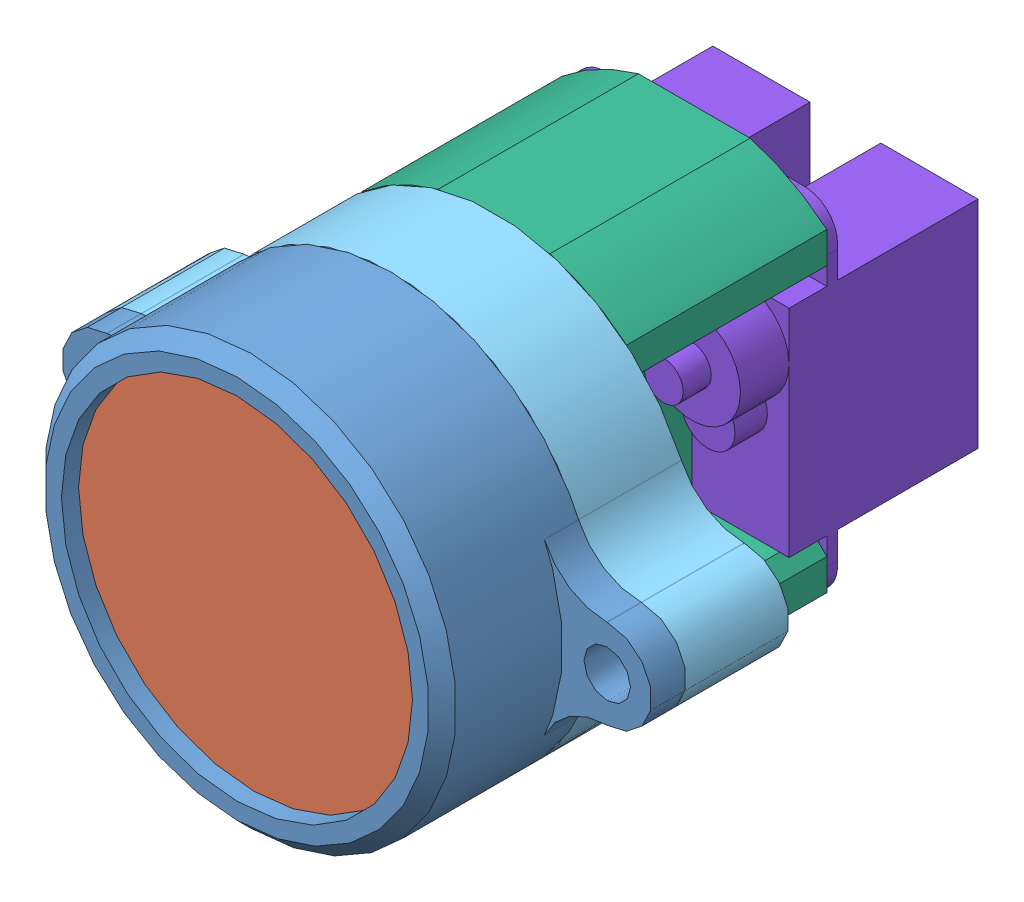
SolidWorks assembly Battery Voltage Indicator, configuration Default. Lengths in mm.
Overall size (132.95 120.76 56.35).
32 component instances, 13 part files, 60 mates.
Components (placement in the parent):
- 1.5 IN Case-1: 1.5 IN Case [Default] x (1 0 0) z (0 -1 0) size (54.61 14.29 38.1)
- 1.5 Indicator Glass-1: 1.5 Indicator Glass [Default] at (0 0 -1.5875) x (-1 0 0) z (0 0 -1) size (32.84 32.84 1.59)
- Battery Voltage Indicator Spacer-1: Battery Voltage Indicator Spacer [Default] at (0 0 -3.175) x (-1 0 0) z (0 0 -1) size (32.84 32.84 6.35)
- Battery Voltage Indicator Bezel Face-1: Battery Voltage Indicator Bezel Face [Default] at (0 0 -11.1125) x (-1 0 0) z (0 0 1) size (32.84 32.84 1.59)
- 1.5 Indicator Rear Bezel Spacer-1: 1.5 Indicator Rear Bezel Spacer [Default] at (0 0 -11.1125) x (1 0 0) z (0 0 -1) size (54.61 38.1 12.7)
- Battery Voltage Servo Mount-1: Battery Voltage Servo Mount [Default] at (0 0 -23.8125) x (1 0 0) z (0 0 -1) size (24.55 36.67 18.54)
- Battery Voltage Pointer-1: Battery Voltage Pointer [#1 Needle] at (0 0 -9.525) x (0.438476 0.898743 0) z (0 0 1) size (8.26 15.24 1.59)
- spur gear_ai-2: spur gear_ai [PreviewCfg] at (0 0 -25.4) x (0 0 -1) z (0.923728 0.383049 0) size (12.7 86.43 86.43)
- spur gear_ai-3: spur gear_ai [PreviewCfg] at (-7.7766 5.5 -38.1) x (0 0 1) z (-0.47771 -0.878518 0) size (12.7 86.43 86.43)
- SERVO, SUB-NANO, 3.7G, GENERIC-2: SERVO, SUB-NANO, 3.7G, GENERIC [Default] at (-12.2766 -10 -56.35) size (9.5 32.5 24.6)
- Battery Voltage Pointer-2: Battery Voltage Pointer [#2 Needle] at (0 0 -7.1437) x (0.44703 -0.894519 0) z (0 0 1) size (8.26 15.24 1.59)
- spur gear_ai-4: spur gear_ai [PreviewCfg] at (0 0 -30.1625) x (0 0 -1) z (0.923728 0.383049 0) size (12.7 86.43 86.43)
- spur gear_ai-5: spur gear_ai [PreviewCfg] at (7.7766 5.5 -33.3375) x (0 0 1) z (-0.486959 -0.873425 0) size (12.7 86.43 86.43)
- SERVO, SUB-NANO, 3.7G, GENERIC-1: SERVO, SUB-NANO, 3.7G, GENERIC [Default] at (3.2766 -10 -56.35) size (9.5 32.5 24.6)
- 93365A130_BRASS HEAT-SET INSERT FOR PLASTICS_6-32-3: 93365A130_BRASS HEAT-SET INSERT FOR PLASTICS_6-32 [93365A130] at (-23.1775 0 -14.2875) x (1 0 0) z (0 -1 0) size (5.56 4.29 5.56)
- 93365A130_BRASS HEAT-SET INSERT FOR PLASTICS_6-32-4: 93365A130_BRASS HEAT-SET INSERT FOR PLASTICS_6-32 [93365A130] at (23.1775 0 -14.2875) x (0.987351 0.158553 0) z (0.158553 -0.987351 0) size (5.56 4.29 5.56)
- 93365A102 - INSERT, 0-80, BRASS, FOR PLASTICS-1: 93365A102 - INSERT, 0-80, BRASS, FOR PLASTICS [Default] at (-7.7766 -13 -42.35) x (-0.989224 0.146409 0) z (-0.146409 -0.989224 0) size (3.58 3.01 3.58)
- 91772A061_18-8 SS PAN HEAD PHILLIPS MACHINE SCREW_#0-80 X .2812-1: 91772A061_18-8 SS PAN HEAD PHILLIPS MACHINE SCREW_#0-80 X .2812 [91772A061] at (-7.7766 -13 -36.2063) x (-0.460399 -0.887712 0) z (0 0 -1) size (2.95 2.95 8.26)
- 93365A102 - INSERT, 0-80, BRASS, FOR PLASTICS-2: 93365A102 - INSERT, 0-80, BRASS, FOR PLASTICS [Default] at (-7.7766 13 -42.35) x (-0.989224 0.146409 0) z (-0.146409 -0.989224 0) size (3.58 3.01 3.58)
- 93365A102 - INSERT, 0-80, BRASS, FOR PLASTICS-3: 93365A102 - INSERT, 0-80, BRASS, FOR PLASTICS [Default] at (7.7766 13 -42.35) x (-0.989224 0.146409 0) z (-0.146409 -0.989224 0) size (3.58 3.01 3.58)
- 93365A102 - INSERT, 0-80, BRASS, FOR PLASTICS-4: 93365A102 - INSERT, 0-80, BRASS, FOR PLASTICS [Default] at (7.7766 -13 -42.35) x (-0.989224 0.146409 0) z (-0.146409 -0.989224 0) size (3.58 3.01 3.58)
- 93365A102 - INSERT, 0-80, BRASS, FOR PLASTICS-5: 93365A102 - INSERT, 0-80, BRASS, FOR PLASTICS [Default] at (7.435 -14.69 -23.8125) x (0.989224 0.146409 0) z (0.146409 -0.989224 0) size (3.58 3.01 3.58)
- 93365A102 - INSERT, 0-80, BRASS, FOR PLASTICS-6: 93365A102 - INSERT, 0-80, BRASS, FOR PLASTICS [Default] at (-7.7474 -14.6946 -23.8125) x (0.989224 0.146409 0) z (0.146409 -0.989224 0) size (3.58 3.01 3.58)
- 93365A102 - INSERT, 0-80, BRASS, FOR PLASTICS-7: 93365A102 - INSERT, 0-80, BRASS, FOR PLASTICS [Default] at (7.435 14.69 -23.8125) x (0.989224 0.146409 0) z (0.146409 -0.989224 0) size (3.58 3.01 3.58)
- 93365A102 - INSERT, 0-80, BRASS, FOR PLASTICS-8: 93365A102 - INSERT, 0-80, BRASS, FOR PLASTICS [Default] at (-7.7474 14.6946 -23.8125) x (0.989224 0.146409 0) z (0.146409 -0.989224 0) size (3.58 3.01 3.58)
- 91772A061_18-8 SS PAN HEAD PHILLIPS MACHINE SCREW_#0-80 X .2812-2: 91772A061_18-8 SS PAN HEAD PHILLIPS MACHINE SCREW_#0-80 X .2812 [91772A061] at (-7.7766 13 -36.2063) x (-0.460399 -0.887712 0) z (0 0 -1) size (2.95 2.95 8.26)
- 91772A061_18-8 SS PAN HEAD PHILLIPS MACHINE SCREW_#0-80 X .2812-3: 91772A061_18-8 SS PAN HEAD PHILLIPS MACHINE SCREW_#0-80 X .2812 [91772A061] at (7.7766 13 -36.2063) x (-0.460399 -0.887712 0) z (0 0 -1) size (2.95 2.95 8.26)
- 91772A061_18-8 SS PAN HEAD PHILLIPS MACHINE SCREW_#0-80 X .2812-4: 91772A061_18-8 SS PAN HEAD PHILLIPS MACHINE SCREW_#0-80 X .2812 [91772A061] at (7.7766 -13 -36.2063) x (-0.460399 -0.887712 0) z (0 0 -1) size (2.95 2.95 8.26)
- 91772A064 - PHS, 0-80 x .4375, 18-8-1: 91772A064 - PHS, 0-80 x .4375, 18-8 [91772A064] at (7.435 -14.69 -28.575) x (-0.800587 -0.599216 0) z (0 0 1) size (2.95 2.95 12.24)
- 91772A064 - PHS, 0-80 x .4375, 18-8-2: 91772A064 - PHS, 0-80 x .4375, 18-8 [91772A064] at (-7.7474 -14.6946 -28.575) x (-0.800587 -0.599216 0) z (0 0 1) size (2.95 2.95 12.24)
- 91772A064 - PHS, 0-80 x .4375, 18-8-3: 91772A064 - PHS, 0-80 x .4375, 18-8 [91772A064] at (7.435 14.69 -28.575) x (-0.800587 -0.599216 0) z (0 0 1) size (2.95 2.95 12.24)
- 91772A064 - PHS, 0-80 x .4375, 18-8-4: 91772A064 - PHS, 0-80 x .4375, 18-8 [91772A064] at (-7.7474 14.6946 -28.575) x (-0.800587 -0.599216 0) z (0 0 1) size (2.95 2.95 12.24)
Mates (geometry in assembly coordinates):
- Coincident1: coincident aligned: plane of 1.5 IN Case-1 through (0 0 0) normal (1 0 0); plane of assembly through (0 0 0) normal (1 0 0)
- Coincident2: coincident aligned: plane of 1.5 IN Case-1 through (0 0 0) normal (0 0 1); plane of assembly through (0 0 0) normal (0 0 1)
- Coincident3: coincident anti-aligned: plane of 1.5 IN Case-1 through (0 0 0) normal (0 -1 0); plane of assembly through (0 0 0) normal (0 1 0)
- InPlace1: in place: plane of 1.5 IN Case-1 through (0 0 -1.5875) normal (0 0 -1); plane of 1.5 Indicator Glass-1 through (0 0 -1.5875) normal (0 0 -1); moOrthogonalPlaneRef_w of 1.5 IN Case-1 through (0 0 -1.5875) normal (0 0 -1); unknown of 1.5 Indicator Glass-1; plane of 1.5 IN Case-1 through (0 0 -1.5875) normal (0 0 -1); plane of 1.5 Indicator Glass-1 through (0 0 -1.5875) normal (-1 0 0); plane of 1.5 IN Case-1 through (0 0 -1.5875) normal (0 0 -1); unknown of 1.5 Indicator Glass-1
- Coincident4: coincident aligned: plane of ?; plane of ?
- Coincident5: coincident aligned: moOrthogonalPlaneRef_w of 1.5 IN Case-1 through (0 0 -1.5875) normal (0 1 0); plane of 1.5 Indicator Glass-1 through (0 0 -1.5875) normal (0 1 0)
- Coincident6: coincident anti-aligned: moOrthogonalPlaneRef_w of 1.5 IN Case-1 through (0 0 -1.5875) normal (1 0 0); plane of 1.5 Indicator Glass-1 through (0 0 -1.5875) normal (-1 0 0)
- InPlace2: in place: plane of 1.5 Indicator Glass-1 through (0 0 -3.175) normal (0 0 -1); plane of Battery Voltage Indicator Spacer-1 through (0 0 -3.175) normal (0 0 -1); plane of 1.5 Indicator Glass-1 through (0 0 -3.175) normal (0 0 -1); unknown of Battery Voltage Indicator Spacer-1; plane of 1.5 Indicator Glass-1 through (0 0 -3.175) normal (0 0 -1); plane of Battery Voltage Indicator Spacer-1 through (0 0 -3.175) normal (-1 0 0); plane of 1.5 Indicator Glass-1 through (0 0 -3.175) normal (0 0 -1); unknown of Battery Voltage Indicator Spacer-1
- Coincident7: coincident aligned: plane of ?; plane of ?
- Coincident8: coincident aligned: moOrthogonalPlaneRef_w of 1.5 Indicator Glass-1 through (0 0 -3.175) normal (0 1 0); plane of Battery Voltage Indicator Spacer-1 through (0 0 -3.175) normal (0 1 0)
- Coincident9: coincident anti-aligned: moOrthogonalPlaneRef_w of 1.5 Indicator Glass-1 through (0 0 -3.175) normal (1 0 0); plane of Battery Voltage Indicator Spacer-1 through (0 0 -3.175) normal (-1 0 0)
- Concentric1: concentric anti-aligned: cylinder of 1.5 IN Case-1 through (0 0 -1.5875) axis (0 0 1) radius 19.05; cylinder of Battery Voltage Indicator Bezel Face-1 through (0 0 -9.525) axis (0 0 -1) radius 16.4211
- Coincident13: coincident anti-aligned: plane of Battery Voltage Indicator Bezel Face-1 through (0 0 -11.1125) normal (-1 0 0); plane of assembly through (0 0 0) normal (1 0 0)
- Coincident14: coincident anti-aligned: plane of Battery Voltage Indicator Spacer-1 through (0 0 -9.525) normal (0 0 -1); plane of Battery Voltage Indicator Bezel Face-1 through (0 0 -9.525) normal (0 0 1)
- Concentric30: concentric aligned: cylinder of Needle #2 Concentric Needle Shaft-1 through (0 0 0.1538) axis (0 0 -1) radius 3.175; cylinder of Battery Voltage Pointer-1 through (0 0 -7.9375) axis (0 0 -1) radius 3.302
- Concentric31: concentric anti-aligned: cylinder of Needle #1 Concetric Needle Shaft-1 through (0 0 -46.3964) axis (0 0 1) radius 1.5875; cylinder of Battery Voltage Pointer-2 through (0 0 -5.5563) axis (0 0 -1) radius 1.651
- Distance11: distance = 0.7937 mm anti-aligned: plane of Battery Voltage Pointer-1 through (0 0 -7.9375) normal (0 0 1); plane of Battery Voltage Pointer-2 through (0 0 -7.1437) normal (0 0 -1)
- Concentric63: concentric aligned: cylinder of 1.5 IN Case-1 through (0 0 -64.994) axis (0 0 1) radius 16.6687; cylinder of 1.5 Indicator Rear Bezel Spacer-1 through (0 0 -17.4625) axis (0 0 1) radius 3.302
- Concentric64: concentric aligned: cylinder of 1.5 IN Case-1 through (-23.1775 0 -14.2875) axis (0 0 1) radius 4.1275; cylinder of 1.5 Indicator Rear Bezel Spacer-1 through (-23.1775 0 -23.8125) axis (0 0 1) radius 4.1275
- Coincident109: coincident anti-aligned: plane of 1.5 IN Case-1 through (0 0 -14.2875) normal (0 0 -1); plane of 1.5 Indicator Rear Bezel Spacer-1 through (23.1775 0 -14.2875) normal (0 0 1)
- Concentric65: concentric aligned: cylinder of Battery Voltage Indicator Bezel Face-1 through (0 0 -9.525) axis (0 0 -1) radius 3.302; cylinder of Battery Voltage Pointer-1 through (0 0 -7.9375) axis (0 0 -1) radius 4.1275
- Coincident110: coincident: plane of assembly; plane of Battery Voltage Indicator Bezel Face-1 through (0 0 -9.525) normal (0 0 1); plane of Battery Voltage Pointer-1 through (0 0 -9.525) normal (0 0 -1)
- Concentric66: concentric aligned: cylinder of Battery Voltage Pointer-1 through (0 0 -7.9375) axis (0 0 -1) radius 3.302; cylinder of Battery Voltage Pointer-2 through (0 0 -5.5563) axis (0 0 -1) radius 4.1275
- Coincident111: coincident aligned: plane of Battery Voltage Pointer-2 through (0 0 -5.5563) normal (0 0 1); plane of Needle #1 Concetric Needle Shaft-1 through (0 0 -5.5563) normal (0 0 1)
- Coincident112: coincident aligned: plane of Battery Voltage Pointer-1 through (0 0 -7.9375) normal (0 0 1); plane of Needle #2 Concentric Needle Shaft-1 through (0 0 -7.9375) normal (0 0 1)
- Concentric67: concentric anti-aligned: cone of 1.5 Indicator Rear Bezel Spacer-1 through (-23.1775 0 -14.2875) axis (0 0 -1); cylinder of 93365A130_BRASS HEAT-SET INSERT FOR PLASTICS_6-32-3 through (-23.1775 0 -14.2875) axis (0 0 1) radius 2.5273
- Coincident113: coincident aligned: plane of 1.5 Indicator Rear Bezel Spacer-1 through (23.1775 0 -14.2875) normal (0 0 1); plane of 93365A130_BRASS HEAT-SET INSERT FOR PLASTICS_6-32-3 through (-23.1775 0 -14.2875) normal (0 0 1)
- Coincident114: coincident aligned: plane of 1.5 Indicator Rear Bezel Spacer-1 through (23.1775 0 -14.2875) normal (0 0 1); plane of 93365A130_BRASS HEAT-SET INSERT FOR PLASTICS_6-32-4 through (23.1775 0 -14.2875) normal (0 0 1)
- Concentric68: concentric anti-aligned: cone of 1.5 Indicator Rear Bezel Spacer-1 through (23.1775 0 -14.2875) axis (0 0 -1); cylinder of 93365A130_BRASS HEAT-SET INSERT FOR PLASTICS_6-32-4 through (23.1775 0 -14.2875) axis (0 0 1) radius 2.5273
- Parallel1: parallel anti-aligned: plane of 1.5 Indicator Rear Bezel Spacer-1 through (23.1775 0 -23.8125) normal (0 0 -1); plane of SERVO, SUB-NANO, 3.7G, GENERIC-1 through (12.2866 -9.99 -42.35) normal (0 0 1)
- Coincident116: coincident: plane of SERVO, SUB-NANO, 3.7G, GENERIC-1 through (5.9666 3.69 -31.75) normal (0 0 1); plane of GEAR, SPUR, 18T, 20PD X .417 OD X 5-64BD X .125 THK-2 through (7.7766 5.5 -31.75) normal (0 0 -1)
- Concentric71: concentric: cylinder of Battery Voltage Pointer-1 through (0 0 -7.9375) axis (0 0 -1) radius 3.302; cylinder of SHAFT, NEEDLE #1, DUAL POINTER-2 through (0 0 -7.9375) axis (0 0 -1) radius 3.175
- Coincident117: coincident: plane of Battery Voltage Pointer-1 through (0 0 -7.9375) normal (0 0 1); plane of SHAFT, NEEDLE #1, DUAL POINTER-2 through (0 0 -7.9375) normal (0 0 1)
- Concentric72: concentric: cylinder of Battery Voltage Pointer-2 through (0 0 -5.5563) axis (0 0 -1) radius 1.651; cylinder of SHAFT, NEEDLE #2, DUAL POINTER-1 through (0 0 -5.5563) axis (0 0 -1) radius 1.5875
- Coincident118: coincident: plane of Battery Voltage Pointer-2 through (0 0 -5.5563) normal (0 0 1); plane of SHAFT, NEEDLE #2, DUAL POINTER-1 through (0 0 -5.5563) normal (0 0 1)
- Parallel2: parallel anti-aligned: plane of SERVO, SUB-NANO, 3.7G, GENERIC-1 through (3.2766 12.51 -56.36) normal (-1 0 0)
- Symmetric1: symmetric aligned: plane of SERVO, SUB-NANO, 3.7G, GENERIC-1 through (3.2666 -10 -56.36) normal (0 -1 0); plane of SERVO, SUB-NANO, 3.7G, GENERIC-1 through (12.2866 10 -56.36) normal (0 1 0)
- Parallel3: parallel anti-aligned: plane of SERVO, SUB-NANO, 3.7G, GENERIC-1 through (3.2766 12.51 -56.36) normal (-1 0 0); plane of SERVO, SUB-NANO, 3.7G, GENERIC-2 through (-3.2766 -12.51 -56.36) normal (1 0 0)
- Coincident121: coincident aligned: plane of SERVO, SUB-NANO, 3.7G, GENERIC-1 through (3.2666 -9.99 -43.35) normal (0 0 -1); plane of SERVO, SUB-NANO, 3.7G, GENERIC-2 through (-12.2866 -9.99 -43.35) normal (0 0 -1)
- Coincident122: coincident aligned: plane of SERVO, SUB-NANO, 3.7G, GENERIC-1 through (3.2666 -10 -56.36) normal (0 -1 0); plane of SERVO, SUB-NANO, 3.7G, GENERIC-2 through (-12.2866 -10 -56.36) normal (0 -1 0)
- InPlace3: in place: plane of 1.5 Indicator Rear Bezel Spacer-1 through (23.1775 0 -23.8125) normal (0 0 -1); plane of ? through (0 0 -23.8125) normal (0 0 -1); plane of 1.5 Indicator Rear Bezel Spacer-1 through (23.1775 0 -23.8125) normal (0 0 -1); plane of ? through (0 0 -23.8125) normal (0 1 0); plane of 1.5 Indicator Rear Bezel Spacer-1 through (23.1775 0 -23.8125) normal (0 0 -1); plane of ? through (0 0 -23.8125) normal (-1 0 0); plane of 1.5 Indicator Rear Bezel Spacer-1 through (23.1775 0 -23.8125) normal (0 0 -1); unknown of Battery Voltage Servo Mount-1
- Coincident123: coincident aligned: plane of ?; plane of ?
- Coincident124: coincident aligned: moOrthogonalPlaneRef_w of 1.5 Indicator Rear Bezel Spacer-1 through (0 0 -23.8125) normal (0 -1 0); plane of Part4^Battery Voltage Indicator-1 through (0 0 -23.8125) normal (0 -1 0)
- Coincident125: coincident anti-aligned: moOrthogonalPlaneRef_w of 1.5 Indicator Rear Bezel Spacer-1 through (0 0 -23.8125) normal (-1 0 0); plane of Part4^Battery Voltage Indicator-1 through (0 0 -23.8125) normal (1 0 0)
- Coincident126: coincident: plane of SERVO, SUB-NANO, 3.7G, GENERIC-2 through (-9.5866 3.69 -31.75) normal (0 0 1); plane of GEAR, SPUR, 18T, 20PD X .417 OD X 5-64BD X .125 THK-3 through (-7.7766 5.5 -31.75) normal (0 0 -1)
- Concentric74: concentric: cylinder of SERVO, SUB-NANO, 3.7G, GENERIC-1 through (7.7766 5.5 -31.75) axis (0 0 -1) radius 1.8; cylinder of GEAR, SPUR, 18T, 20PD X .417 OD X 5-64BD X .125 THK-2 through (7.7766 5.5 -22.3048) axis (0 0 -1) radius 2.7781
- Coincident127: coincident aligned: plane of SHAFT, NEEDLE #1, DUAL POINTER-2 through (0 0 -25.4) normal (0 0 1); plane of GEAR, SPUR, 18T, 20PD X .417 OD X 5-64BD X .125 THK-3 through (-7.7766 5.5 -25.4) normal (0 0 1)
- Concentric75: concentric: cylinder of SERVO, SUB-NANO, 3.7G, GENERIC-2 through (-7.7766 5.5 -31.75) axis (0 0 -1) radius 1.8; cylinder of GEAR, SPUR, 18T, 20PD X .417 OD X 5-64BD X .125 THK-3 through (-7.7766 5.5 -31.75) axis (0 0 1) radius 3.175
- Coincident128: coincident aligned: plane of Battery Voltage Servo Mount-1 through (-12.2766 10.3969 -68.1543) normal (-1 0 0); plane of Part4^Battery Voltage Indicator-2 through (-12.1084 -12.3129 -66.9354) normal (-1 0 0)
- Coincident129: coincident aligned: plane of Battery Voltage Servo Mount-1 through (-12.2867 9.99 -42.35) normal (0 0 -1); plane of Part4^Battery Voltage Indicator-2 through (12.0842 -11.906 -42.1123) normal (0 0 -1)
- Coincident130: coincident aligned: plane of SERVO, SUB-NANO, 3.7G, GENERIC-2 through (-6.7666 -16 -42.34) normal (0 -1 0); plane of Part4^Battery Voltage Indicator-2 through (11.935 -16 -67.1731) normal (0 -1 0)
- Concentric76: concentric aligned: cone of Part4^Battery Voltage Indicator-1 through (-7.7766 -13 -42.35) axis (0 0 1); cone of 93365A102 - INSERT, 0-80, BRASS, FOR PLASTICS-1 through (-7.7766 -13 -41.24) axis (0 0 1)
- Coincident131: coincident aligned: plane of Part4^Battery Voltage Indicator-1 through (-12.2867 9.99 -42.35) normal (0 0 -1); plane of 93365A102 - INSERT, 0-80, BRASS, FOR PLASTICS-1 through (-6.0052 -13.2622 -42.35) normal (0 0 -1)
- Concentric77: concentric aligned: cone of Part4^Battery Voltage Indicator-1 through (7.435 -14.69 -23.8125) axis (0 0 -1); cone of 93365A102 - INSERT, 0-80, BRASS, FOR PLASTICS-5 through (7.435 -14.69 -24.9225) axis (0 0 -1)
- Coincident132: coincident aligned: plane of Part4^Battery Voltage Indicator-1 through (0 0 -23.8125) normal (0 0 1); plane of 93365A102 - INSERT, 0-80, BRASS, FOR PLASTICS-5 through (5.6636 -14.9522 -23.8125) normal (0 0 1)
- Concentric78: concentric anti-aligned: circle of 93365A102 - INSERT, 0-80, BRASS, FOR PLASTICS-1; cylinder of 91772A061_18-8 SS PAN HEAD PHILLIPS MACHINE SCREW_#0-80 X .2812-1 through (-7.7766 -13 -36.2063) axis (0 0 1) radius 1.4732
- Coincident133: coincident anti-aligned: plane of SERVO, SUB-NANO, 3.7G, GENERIC-2 through (-12.2866 -9.99 -43.35) normal (0 0 -1); plane of 91772A061_18-8 SS PAN HEAD PHILLIPS MACHINE SCREW_#0-80 X .2812-1 through (-7.7766 -13 -43.35) normal (0 0 1)
- Concentric79: concentric anti-aligned: circle of 93365A102 - INSERT, 0-80, BRASS, FOR PLASTICS-5; cylinder of 91772A064 - PHS, 0-80 x .4375, 18-8-1 through (7.435 -14.69 -28.575) axis (0 0 -1) radius 1.4732
- Coincident134: coincident anti-aligned: plane of 1.5 Indicator Rear Bezel Spacer-1 through (8.3621 -14.6946 -17.4625) normal (0 0 1); plane of 91772A064 - PHS, 0-80 x .4375, 18-8-1 through (7.435 -14.69 -17.4625) normal (0 0 -1)
- Tangent3: tangent: circle of SHAFT, NEEDLE #2, DUAL POINTER-1; circle of GEAR, SPUR, 18T, 20PD X .417 OD X 5-64BD X .125 THK-2
